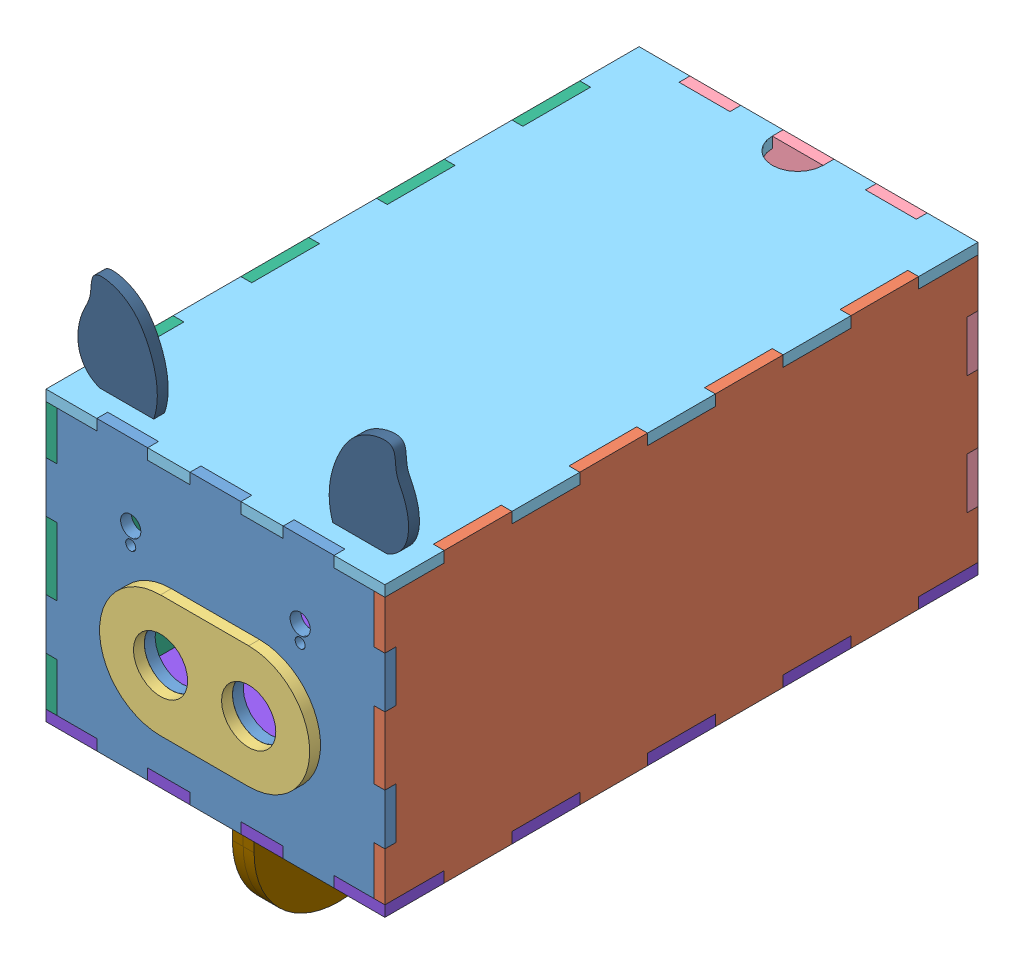
SolidWorks assembly PiggyBot, configuration Default. Lengths in mm.
Overall size (100 149.81 178.2).
14 component instances, 11 part files, 36 mates.
Components (placement in the parent):
- Front-2: Front [Default] at (-25.5857 55.2837 79.9595) size (100 108.73 3.2)
- side-2: side [Default] at (21.2143 55.2837 -4.3405) size (3.2 85 175)
- nose-2: nose [Default] at (-25.5857 47.2837 83.1595) size (62 36 3.2)
- Back-2: Back [Default] at (-25.5857 55.2837 -91.8405) size (100 85 3.2)
- Top-2: Top [Default] at (-25.5857 94.5837 -4.3405) x (0 0 -1) z (1 0 0) size (175 3.2 100)
- side_battery-1: side_battery [Default] at (-75.5857 55.2837 -4.3405) x (1 0 0) z (0 0 -1) size (3.2 85 175)
- Battery_Holder_01-1: Battery_Holder_01 [Default] at (-75.5857 30.9837 -29.3405) x (0 0 -1) z (1 0 0) size (3.2 25 25.2)
- Battery_Holder_01-2: Battery_Holder_01 [Default] at (-75.5857 30.9837 23.8595) x (0 0 -1) z (1 0 0) size (3.2 25 25.2)
- Battery_Holder_02-1: Battery_Holder_02 [Default] at (-50.3857 45.9837 -32.5405) x (0 0 1) z (-1 0 0) size (56.4 25 0)
- Bottom-3: Bottom [Default] at (-25.5857 12.7837 -4.3405) x (0 0 -1) z (1 0 0) size (175 3.2 100)
- balance-1: balance [Default] at (-25.5857 -5.6042 44.118) x (1 0 0) z (0 0 -1) size (3.2 39.2 50)
- balance-2: balance [Default] at (-28.7857 -5.6042 44.118) x (1 0 0) z (0 0 -1) size (3.2 39.2 50)
- ear-1: ear [Default] at (-65.5857 97.7837 71.7595) size (24.03 32.01 3.2)
- ear-2: ear [Default] at (14.4143 97.7837 74.9595) x (-1 0 0) z (0 0 -1) size (24.03 32.01 3.2)
Mates (geometry in assembly coordinates):
- Coincident2: coincident anti-aligned: plane of Front-2 through (21.2143 94.5837 83.1595) normal (1 0 0); plane of side-2 through (21.2143 55.2837 -4.3405) normal (-1 0 0)
- Coincident4: coincident aligned: plane of Front-2 through (-25.5857 55.2837 83.1595) normal (0 0 1); plane of side-2 through (24.4143 94.5837 83.1595) normal (0 0 1)
- Coincident5: coincident anti-aligned: plane of Front-2 through (21.2143 80.2837 83.1595) normal (0 1 0); plane of side-2 through (24.4143 80.2837 79.9595) normal (0 -1 0)
- Coincident7: coincident anti-aligned: plane of Front-2 through (-25.5857 55.2837 83.1595) normal (0 0 1); plane of nose-2 through (-38.5857 47.2837 83.1595) normal (0 0 -1)
- Concentric1: concentric aligned: cylinder of Front-2 through (-38.5857 47.2837 83.1595) axis (0 0 -1) radius 8; cylinder of nose-2 through (-38.5857 47.2837 86.3595) axis (0 0 -1) radius 8
- Coincident13: coincident aligned: plane of side-2 through (24.4143 55.2837 -4.3405) normal (1 0 0); plane of Back-2 through (24.4143 65.2837 -88.6405) normal (1 0 0)
- Coincident14: coincident aligned: plane of side-2 through (24.4143 97.7837 -54.3405) normal (0 1 0); plane of Back-2 through (9.4143 97.7837 -88.6405) normal (0 1 0)
- Coincident20: coincident aligned: plane of Front-2 through (-25.5857 55.2837 83.1595) normal (0 0 1); plane of Top-2 through (-33.0857 97.7837 83.1595) normal (0 0 1)
- Coincident21: coincident aligned: plane of side-2 through (24.4143 55.2837 -4.3405) normal (1 0 0); plane of Top-2 through (24.4143 97.7837 83.1595) normal (1 0 0)
- Coincident22: coincident aligned: plane of side-2 through (24.4143 97.7837 -54.3405) normal (0 1 0); plane of Top-2 through (-25.5857 97.7837 -88.6405) normal (0 1 0)
- Coincident25: coincident aligned: plane of side_battery-1 through (-72.3857 12.7837 5.6595) normal (0 -1 0); plane of Back-2 through (-60.5857 12.7837 -88.6405) normal (0 -1 0)
- Coincident26: coincident aligned: plane of Back-2 through (-75.5857 65.2837 -88.6405) normal (-1 0 0); plane of side_battery-1 through (-75.5857 55.2837 -4.3405) normal (-1 0 0)
- Coincident27: coincident aligned: plane of Back-2 through (-25.5857 55.2837 -91.8405) normal (0 0 -1); plane of side_battery-1 through (-72.3857 94.5837 -91.8405) normal (0 0 -1)
- Coincident30: coincident aligned: plane of side_battery-1 through (-75.5857 55.2837 -4.3405) normal (-1 0 0); plane of Battery_Holder_01-1 through (-75.5857 30.9837 -32.5405) normal (-1 0 0)
- Coincident31: coincident anti-aligned: plane of side_battery-1 through (-72.3857 45.9837 -29.3405) normal (0 0 -1); plane of Battery_Holder_01-1 through (-75.5857 30.9837 -29.3405) normal (0 0 1)
- Coincident32: coincident anti-aligned: plane of side_battery-1 through (-72.3857 45.9837 -32.5405) normal (0 -1 0); plane of Battery_Holder_01-1 through (-75.5857 45.9837 -32.5405) normal (0 1 0)
- Coincident35: coincident aligned: plane of side_battery-1 through (-75.5857 55.2837 -4.3405) normal (-1 0 0); plane of Battery_Holder_01-2 through (-75.5857 30.9837 20.6595) normal (-1 0 0)
- Coincident36: coincident anti-aligned: plane of side_battery-1 through (-72.3857 45.9837 20.6595) normal (0 0 1); plane of Battery_Holder_01-2 through (-75.5857 30.9837 20.6595) normal (0 0 -1)
- Coincident38: coincident anti-aligned: line of side_battery-1 through (-75.5857 30.9837 23.8595) axis (0 0 -1); line of Battery_Holder_01-2 through (-75.5857 30.9837 20.6595) axis (0 0 1)
- Coincident39: coincident: plane of Battery_Holder_02-1 through (-53.5857 45.9837 -32.5405) normal (-1 0 0); plane of Battery_Holder_01-1 through (-53.5857 45.9837 -32.5405) normal (1 0 0)
- Coincident40: coincident: plane of Battery_Holder_01-1 through (-75.5857 30.9837 -32.5405) normal (0 0 -1); plane of Battery_Holder_02-1 through (-53.5857 45.9837 -32.5405) normal (0 0 -1)
- Coincident41: coincident: plane of Battery_Holder_01-1 through (-50.3857 25.9837 -32.5405) normal (0 -1 0); plane of Battery_Holder_02-1 through (-53.5857 25.9837 -29.3405) normal (0 -1 0)
- Coincident43: coincident aligned: plane of Back-2 through (-25.5857 55.2837 -91.8405) normal (0 0 -1); plane of Bottom-3 through (-33.0857 15.9837 -91.8405) normal (0 0 -1)
- Coincident44: coincident aligned: plane of side-2 through (24.4143 55.2837 -4.3405) normal (1 0 0); plane of Bottom-3 through (24.4143 15.9837 83.1595) normal (1 0 0)
- Coincident45: coincident aligned: plane of side-2 through (24.4143 12.7837 45.6595) normal (0 -1 0); plane of Bottom-3 through (-25.5857 12.7837 -4.3405) normal (0 -1 0)
- Coincident46: coincident anti-aligned: plane of balance-1 through (-22.3857 1.7837 49.9595) normal (1 0 0); plane of Bottom-3 through (-22.3857 15.9837 64.9595) normal (-1 0 0)
- Coincident48: coincident aligned: plane of balance-1 through (-22.3857 15.9837 34.9595) normal (0 1 0); plane of Bottom-3 through (-25.5857 15.9837 -4.3405) normal (0 1 0)
- Coincident49: coincident anti-aligned: plane of Bottom-3 through (-28.7857 15.9837 34.9595) normal (0 0 1); plane of balance-1 through (-22.3857 12.7837 34.9595) normal (0 0 -1)
- Coincident50: coincident aligned: plane of balance-2 through (-25.5857 15.9837 34.9595) normal (0 1 0); plane of Bottom-3 through (-25.5857 15.9837 -4.3405) normal (0 1 0)
- Coincident51: coincident anti-aligned: plane of balance-1 through (-25.5857 1.7837 49.9595) normal (-1 0 0); plane of balance-2 through (-25.5857 1.7837 49.9595) normal (1 0 0)
- Coincident52: coincident anti-aligned: plane of Bottom-3 through (-22.3857 15.9837 64.9595) normal (0 0 -1); plane of balance-2 through (-25.5857 15.9837 64.9595) normal (0 0 1)
- Coincident53: coincident aligned: line of Top-2 through (-65.5857 94.5837 74.9595) axis (1 0 0); line of ear-1 through (-65.5857 94.5837 74.9595) axis (1 0 0)
- Coincident54: coincident anti-aligned: line of Top-2 through (-65.5857 94.5837 71.7595) axis (0 0 1); line of ear-1 through (-65.5857 94.5837 74.9595) axis (0 0 -1)
- Coincident59: coincident aligned: plane of Top-2 through (-25.5857 94.5837 -88.6405) normal (0 -1 0); plane of ear-2 through (4.4143 94.5837 71.7595) normal (0 -1 0)
- Coincident60: coincident anti-aligned: plane of Top-2 through (14.4143 97.7837 74.9595) normal (0 0 -1); plane of ear-2 through (14.9143 126.4456 74.9595) normal (0 0 1)
- Coincident61: coincident anti-aligned: plane of Top-2 through (14.4143 97.7837 74.9595) normal (-1 0 0); plane of ear-2 through (14.4143 94.5837 71.7595) normal (1 0 0)
